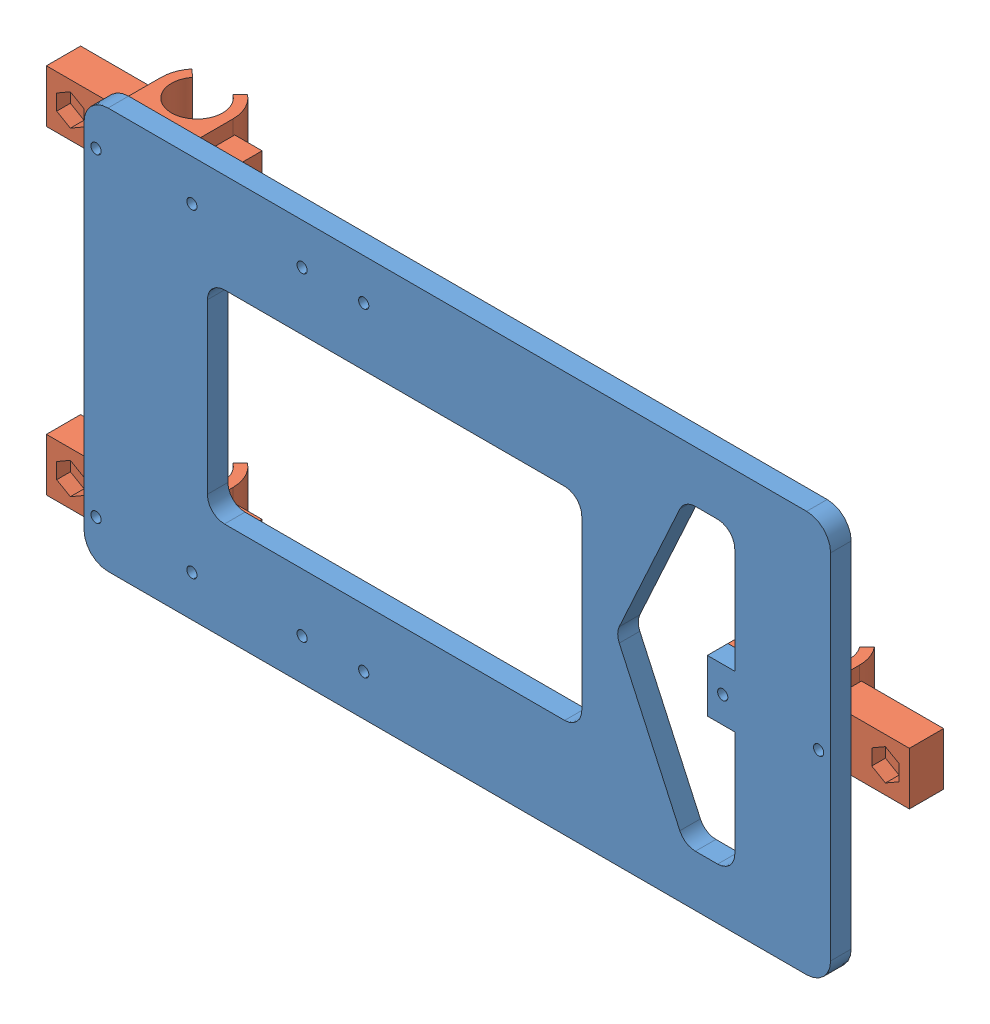
SolidWorks assembly Y Axis, configuration Default. Lengths in mm.
Overall size (252 117.2 23.76).
6 component instances, 4 part files, 16 mates.
Components (placement in the parent):
- Y-frog-1: Y-frog [Default] at (-2.1425 53.5797 156.0498) size (218 117.2 6)
- Y-Bearing-Holder-1: Y-Bearing-Holder [Default] at (-205.3579 297.9233 156.0498) x (-1 0 0) z (0 -1 0) size (53 17.76 24)
- Y-Bearing-Holder-2: Y-Bearing-Holder [Default] at (-205.3579 204.7233 156.0498) x (-1 0 0) z (0 -1 0) size (53 17.76 24)
- Y-Bearing-Holder-3: Y-Bearing-Holder [Default] at (-100.1454 251.3233 156.0498) x (1 0 0) z (0 1 0) size (53 17.76 24)
- heatbed-insulator-1: heatbed-insulator [Default] at (-269.7517 179.3233 182.0498) size (252 219.28 3.6) (hidden)
- Part4^Y Axis-1: Part4^Y Axis [Default] at (-2.1425 53.5797 162.0498) (virtual)
Mates (geometry in assembly coordinates):
- Coincident1: coincident anti-aligned: plane of Y-frog-1 through (-2.1425 53.5797 156.0498) normal (0 0 -1); plane of Y-Bearing-Holder-1 through (-205.3579 297.9233 156.0498) normal (0 0 1)
- Concentric1: concentric anti-aligned: cylinder of Y-frog-1 through (-230.2517 297.9233 162.0498) axis (0 0 -1) radius 1.5; cylinder of Y-Bearing-Holder-1 through (-230.2517 297.9233 146.0498) axis (0 0 1) radius 1.6
- Concentric2: concentric anti-aligned: cylinder of Y-frog-1 through (-258.2517 297.9233 162.0498) axis (0 0 -1) radius 1.5; cylinder of Y-Bearing-Holder-1 through (-258.2517 297.9233 146.0498) axis (0 0 1) radius 1.6
- Coincident2: coincident anti-aligned: plane of Y-frog-1 through (-2.1425 53.5797 156.0498) normal (0 0 -1); plane of Y-Bearing-Holder-2 through (-205.3579 204.7233 156.0498) normal (0 0 1)
- Concentric3: concentric anti-aligned: cylinder of Y-frog-1 through (-230.2517 204.7233 162.0498) axis (0 0 -1) radius 1.5; cylinder of Y-Bearing-Holder-2 through (-230.2517 204.7233 146.0498) axis (0 0 1) radius 1.6
- Concentric4: concentric anti-aligned: cylinder of Y-frog-1 through (-258.2517 204.7233 162.0498) axis (0 0 -1) radius 1.5; cylinder of Y-Bearing-Holder-2 through (-258.2517 204.7233 146.0498) axis (0 0 1) radius 1.6
- Coincident3: coincident anti-aligned: plane of Y-frog-1 through (-2.1425 53.5797 156.0498) normal (0 0 -1); plane of Y-Bearing-Holder-3 through (-100.1454 251.3233 156.0498) normal (0 0 1)
- Concentric5: concentric anti-aligned: cylinder of Y-frog-1 through (-75.2517 251.3233 162.0498) axis (0 0 -1) radius 1.5; cylinder of Y-Bearing-Holder-3 through (-75.2517 251.3233 146.0498) axis (0 0 1) radius 1.6
- Concentric6: concentric anti-aligned: cylinder of Y-frog-1 through (-47.2517 251.3233 162.0498) axis (0 0 -1) radius 1.5; cylinder of Y-Bearing-Holder-3 through (-47.2517 251.3233 146.0498) axis (0 0 1) radius 1.6
- Distance1: distance = 20 mm anti-aligned: plane of heatbed-insulator-1 through (-48.2517 355.8233 182.0498) normal (0 0 -1); plane of Y-frog-1 through (-2.1425 53.5797 162.0498) normal (0 0 1)
- Concentric7: concentric anti-aligned: cylinder of Y-Bearing-Holder-3 through (-33.7517 251.3233 146.0498) axis (0 0 1) radius 2.6; cylinder of heatbed-insulator-1 through (-33.7517 251.3233 185.6498) axis (0 0 -1) radius 2.5
- Concentric8: concentric anti-aligned: cylinder of Y-Bearing-Holder-1 through (-271.7517 297.9233 146.0498) axis (0 0 1) radius 2.6; cylinder of heatbed-insulator-1 through (-271.7517 297.9233 185.6498) axis (0 0 -1) radius 2.5
- InPlace2: in place: plane of Y-frog-1 through (-2.1425 53.5797 162.0498) normal (0 0 1); plane of ? through (0 0 162.0498) normal (0 0 1); moOrthogonalPlaneRef_w of Y-frog-1 through (-2.1425 53.5797 162.0498) normal (0 0 1); plane of ? through (0 0 162.0498) normal (0 1 0); plane of Y-frog-1 through (-2.1425 53.5797 162.0498) normal (0 0 1); plane of ? through (0 0 162.0498) normal (1 0 0); plane of Y-frog-1 through (-2.1425 53.5797 162.0498) normal (0 0 1); unknown of Part4^Y Axis-1
- Coincident8: coincident aligned: plane of Y-frog-1; plane of Part4^Y Axis-1
- Coincident9: coincident aligned: moOrthogonalPlaneRef_w of Y-frog-1 through (-2.1425 53.5797 162.0498) normal (0 1 0); plane of Part4^Y Axis-1 through (-2.1425 53.5797 162.0498) normal (0 1 0)
- Coincident10: coincident anti-aligned: moOrthogonalPlaneRef_w of Y-frog-1 through (-2.1425 53.5797 162.0498) normal (-1 0 0); plane of Part4^Y Axis-1 through (-2.1425 53.5797 162.0498) normal (1 0 0)
